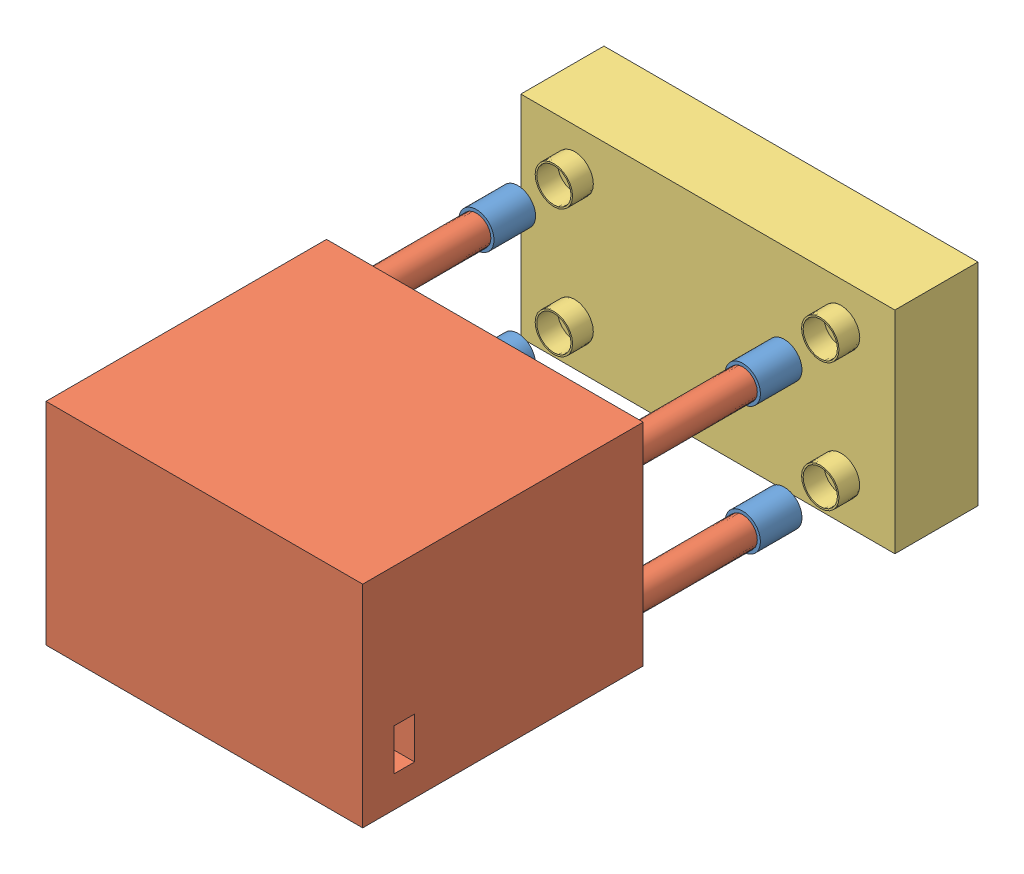
SolidWorks assembly Blood_Rocker, configuration Default. Lengths in mm.
Overall size (180 101.6 282.3).
7 component instances, 4 part files, 12 mates.
Components (placement in the parent):
- Bellow-1: Bellow [Default] at (138.2182 -203.3479 -62.5074) x (-1 0 0) z (0 0 -1) size (17 17 70)
- Blood_Rocker_Base-1: Blood_Rocker_Base [Default] at (74.1182 -234.1479 -52.5074) size (152.4 101.6 195)
- Blood_Rocker_Lid-1: Blood_Rocker_Lid [Default] at (74.1182 -234.1479 -199.8055) size (180 101.6 50)
- Bellow-2: Bellow [Default] at (138.2182 -264.9479 -62.5074) x (-1 0 0) z (0 0 -1) size (17 17 70)
- Bellow-3: Bellow [Default] at (10.0182 -203.3479 -62.5074) x (-1 0 0) z (0 0 -1) size (17 17 70)
- Bellow-4: Bellow [Default] at (10.0182 -264.9479 -62.5074) x (-1 0 0) z (0 0 -1) size (17 17 70)
- Oscillator_Chip-1: Oscillator_Chip [Default] at (74.8432 -234.5979 -46.5074) x (-1 0 0) z (0 0 -1) size (102.55 77.1 25.94)
Mates (geometry in assembly coordinates):
- Coincident1: coincident anti-aligned: plane of Blood_Rocker_Base-1 through (10.0182 -203.3479 -112.5074) normal (0 0 -1); plane of Bellow-3 through (10.0182 -203.3479 -112.5074) normal (0 0 1)
- Concentric1: concentric aligned: cylinder of Blood_Rocker_Base-1 through (10.0182 -203.3479 -112.5074) axis (0 0 1) radius 7; cylinder of Bellow-3 through (10.0182 -203.3479 -132.5074) axis (0 0 1) radius 8.5
- Concentric2: concentric aligned: cylinder of Blood_Rocker_Base-1 through (10.0182 -264.9479 -112.5074) axis (0 0 1) radius 7; cylinder of Bellow-4 through (10.0182 -264.9479 -132.5074) axis (0 0 1) radius 8.5
- Concentric3: concentric aligned: cylinder of Blood_Rocker_Base-1 through (138.2182 -264.9479 -112.5074) axis (0 0 1) radius 7; cylinder of Bellow-2 through (138.2182 -264.9479 -132.5074) axis (0 0 1) radius 8.5
- Concentric4: concentric aligned: cylinder of Bellow-1 through (138.2182 -203.3479 -132.5074) axis (0 0 1) radius 8.5; cylinder of Blood_Rocker_Base-1 through (138.2182 -203.3479 -112.5074) axis (0 0 1) radius 7
- Coincident2: coincident anti-aligned: plane of Bellow-1 through (138.2182 -203.3479 -112.5074) normal (0 0 1); plane of Blood_Rocker_Base-1 through (138.2182 -203.3479 -112.5074) normal (0 0 -1)
- Coincident3: coincident anti-aligned: plane of Blood_Rocker_Base-1 through (138.2182 -264.9479 -112.5074) normal (0 0 -1); plane of Bellow-2 through (138.2182 -264.9479 -112.5074) normal (0 0 1)
- Coincident4: coincident anti-aligned: plane of Blood_Rocker_Base-1 through (10.0182 -264.9479 -112.5074) normal (0 0 -1); plane of Bellow-4 through (10.0182 -264.9479 -112.5074) normal (0 0 1)
- Coincident22: coincident anti-aligned: plane of Blood_Rocker_Base-1 through (74.1182 -234.1479 -46.5074) normal (0 0 -1); plane of Oscillator_Chip-1 through (74.8432 -234.5979 -46.5074) normal (0 0 1)
- Coincident23: coincident anti-aligned: plane of Blood_Rocker_Base-1 through (126.1182 -273.1479 -46.5074) normal (-1 0 0); plane of Oscillator_Chip-1 through (126.1182 -273.1479 -52.4474) normal (1 0 0)
- Coincident24: coincident anti-aligned: plane of Blood_Rocker_Base-1 through (22.1182 -273.1479 -46.5074) normal (0 1 0); plane of Oscillator_Chip-1 through (23.5682 -273.1479 -52.4474) normal (0 -1 0)
- Concentric5: concentric anti-aligned: circle of Blood_Rocker_Lid-1; circle of Bellow-2
